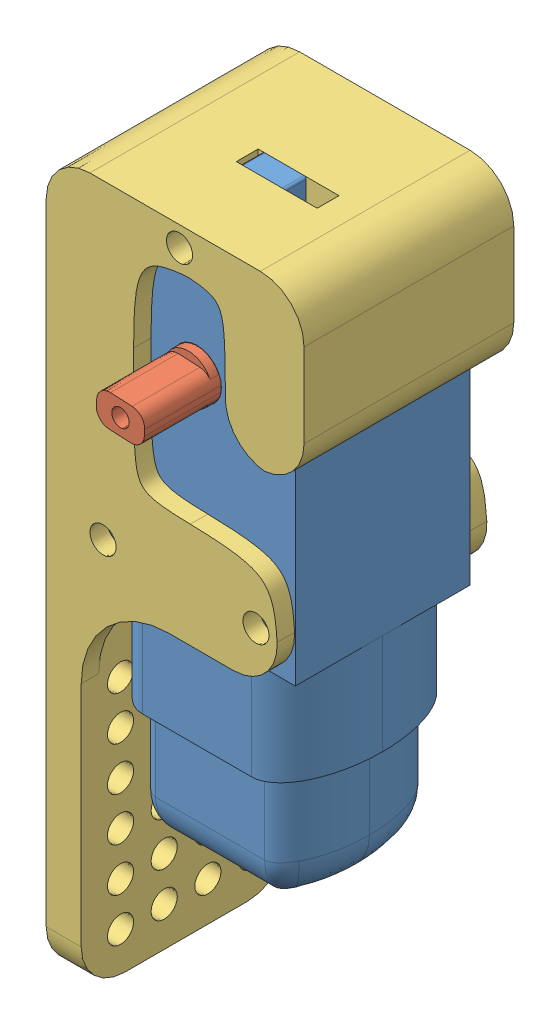
SolidWorks assembly dc_motor, configuration Défaut. Lengths in mm.
Overall size (29.5 82.2 37.5).
3 component instances, 3 part files, 6 mates.
Components (placement in the parent):
- body_gear_motor-1: body_gear_motor [Default] at (1.783 17.0485 64) size (22.6 68.6 21.65)
- axis_gear_motor-1: axis_gear_motor [Default] at (2.1361 31.2398 64) x (-0.998762 0.049736 0) z (0 0 1) size (5.6 5.6 37.5)
- DC_motor_adapter-1: DC_motor_adapter [Défaut] at (-11.467 39.8985 74) x (0 -1 0) z (0 0 1) size (82.2 29.5 24.1)
Mates (geometry in assembly coordinates):
- Coaxiale1: concentric: cylinder of body_gear_motor-1 through (1.783 24.1485 23.75) axis (0 0 1) radius 2.7981; cylinder of axis_gear_motor-1 through (1.783 24.1485 23.75) axis (0 0 1) radius 2.7981
- Distance1: distance = 0 mm: plane of axis_gear_motor-1 through (-7.6203 61.5125 74) normal (0 0 1); plane of body_gear_motor-1 through (13.033 -12.7015 74) normal (0 0 1)
- Coaxiale2: concentric: cylinder of body_gear_motor-1 through (-6.967 4.2985 92.6) axis (0 0 -1) radius 1.5; cylinder of DC_motor_adapter-1 through (-6.967 4.2985 73) axis (0 0 1) radius 1.5
- Coaxiale5: concentric: cylinder of body_gear_motor-1 through (10.533 4.2985 92.6) axis (0 0 -1) radius 1.5; cylinder of DC_motor_adapter-1 through (10.533 4.2985 73) axis (0 0 1) radius 1.5
- Coïncidente5: coincident: plane of body_gear_motor-1 through (13.033 -12.7015 74) normal (0 0 1); plane of DC_motor_adapter-1 through (-11.467 39.8985 74) normal (0 0 -1)
- Coaxiale6: concentric: cylinder of body_gear_motor-1 through (1.783 37.5985 61.9) axis (0 0 1) radius 1.5; cylinder of DC_motor_adapter-1 through (1.783 37.5985 73) axis (0 0 1) radius 1.5
